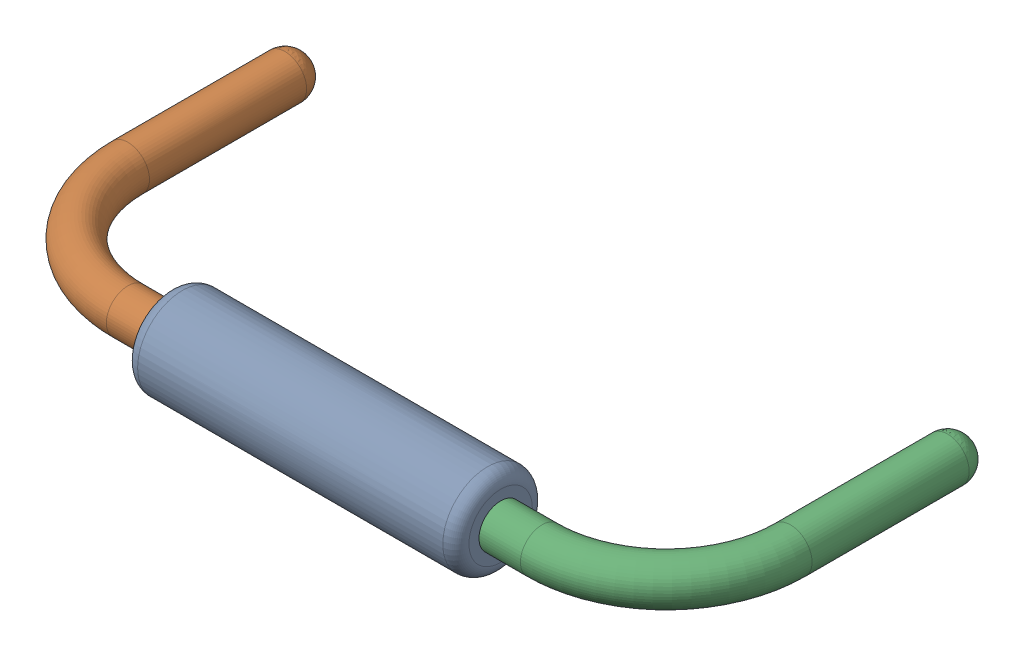
SolidWorks assembly R13, configuration Défaut. Lengths in mm.
Overall size (10.82 1.37 5.33).
4 component instances, 3 part files, 0 mates.
Components (placement in the parent):
- Open CASCADE STEP translator 6.8 1.10.1-1: Open CASCADE STEP translator 6.8 1.10.1 [Défaut] at origin size (10.82 1.37 5.33)
  - Body_1_7-1: Body_1_7 [Défaut] at origin size (5.08 1.37 1.37)
  - Pin_1_4-1: Pin_1_4 [Défaut] at origin size (3.2 0.66 4.98)
  - Pin_2_4-1: Pin_2_4 [Défaut] at (20.32 0 0) x (-1 0 0) z (0 0 1) size (3.2 0.66 4.98)
